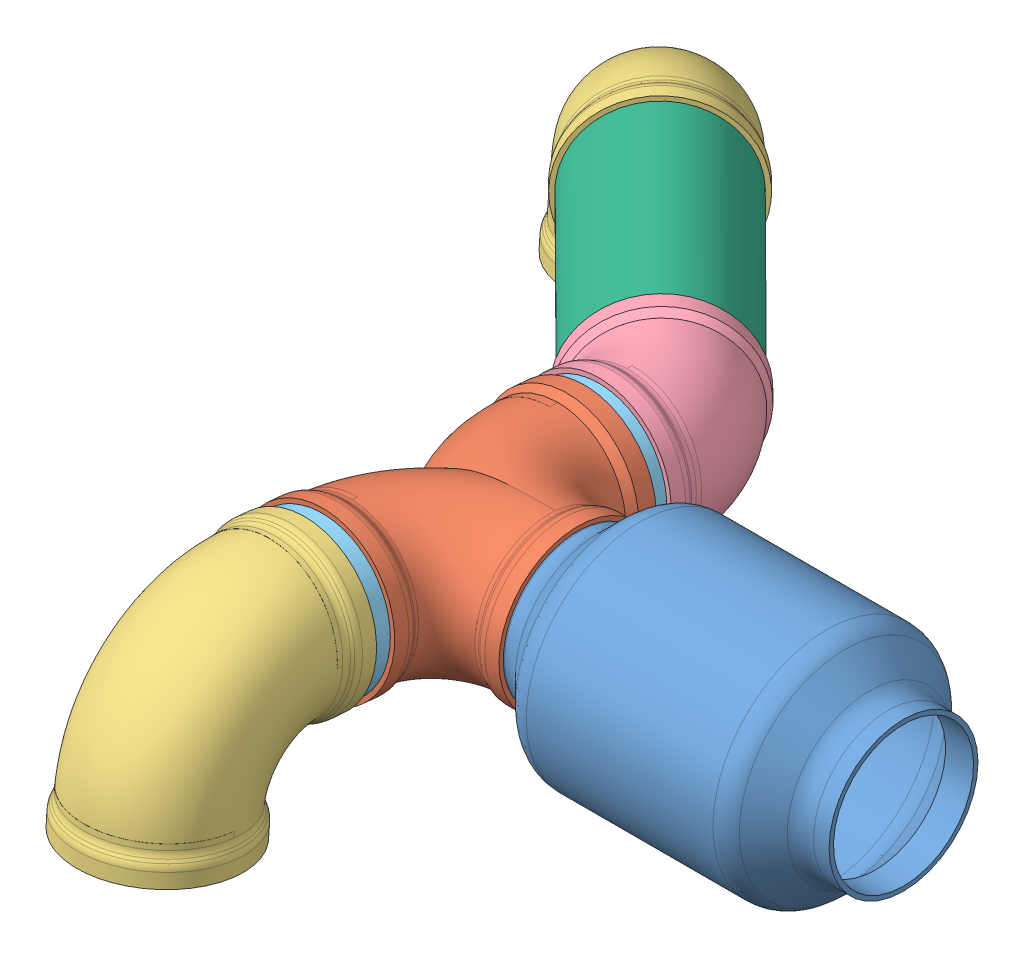
SolidWorks assembly VENTILATION ASSEMBLY, configuration Default. Lengths in mm.
Overall size (657.37 227.14 752.82).
8 component instances, 6 part files, 14 mates.
Components (placement in the parent):
- VENT PUMP-1: VENT PUMP [Default] at (137.9491 134.7321 160.6703) size (246.38 165.1 165.1)
- T CONNECTION-1: T CONNECTION [Default] at (6.0106 134.7321 160.6703) x (0 -0.092149 -0.995745) z (1 0 0) size (190.5 121.73 152.4)
- 90 DEG CONNECTION-1: 90 DEG CONNECTION [Default] at (-70.1894 146.4791 287.6068) x (-0.02224 0.995499 -0.092126) z (0 -0.092149 -0.995745) size (152.4 114.3 152.4)
- 45 DEG CONNECTION-1: 45 DEG CONNECTION [Default] at (-70.1894 123.206 36.1221) x (0.999753 0.022145 -0.002049) z (0 0.092149 0.995745) size (133.42 114.53 126.88)
- 1.33 INCH-1: 1.33 INCH [Default] at (-70.1894 142.56 245.2573) x (0 0.092149 0.995745) z (-0.923944 -0.3809 0.03525) size (33.78 107.95 107.95)
- 1.33 INCH-2: 1.33 INCH [Default] at (-70.1894 124.0122 44.8333) x (0 0.092149 0.995745) z (-0.987138 -0.159192 0.014732) size (33.78 107.95 107.95)
- 8 INCH-3: 8 INCH [Default] at (-254.1069 99.2716 -178.1101) x (0.706932 0.080818 0.702649) z (0.56882 -0.655385 -0.496905) size (228.6 107.95 107.95)
- 90 DEG CONNECTION-2: 90 DEG CONNECTION [Default] at (-260.2915 98.5646 -184.2572) x (-0.02224 0.995499 -0.092126) z (0.706932 0.080818 0.702649) size (152.4 114.3 152.4)
Mates (geometry in assembly coordinates):
- Concentric1: concentric anti-aligned: cylinder of VENT PUMP-1 through (14.7591 134.7321 160.6703) axis (-1 0 0) radius 53.975; cylinder of T CONNECTION-1 through (25.0606 134.7321 160.6703) axis (1 0 0) radius 53.975
- Coincident1: coincident anti-aligned: circle of VENT PUMP-1; circle of T CONNECTION-1
- Coincident2: coincident anti-aligned: circle of T CONNECTION-1; circle of ?
- Coincident3: coincident aligned: circle of ?; circle of 90 DEG CONNECTION-1
- Coincident4: coincident aligned: circle of T CONNECTION-1; circle of ?
- Coincident5: coincident aligned: circle of ?; circle of 45 DEG CONNECTION-1
- Coincident6: coincident aligned: circle of T CONNECTION-1; circle of 1.33 INCH-1
- Coincident7: coincident anti-aligned: circle of 90 DEG CONNECTION-1; circle of 1.33 INCH-1
- Coincident8: coincident aligned: circle of T CONNECTION-1; circle of 1.33 INCH-2
- Coincident9: coincident aligned: circle of 45 DEG CONNECTION-1; circle of 1.33 INCH-2
- Coincident10: coincident aligned: circle of 45 DEG CONNECTION-1; plane of 8 INCH-3 through (-92.5023 117.7466 -17.4845) normal (0.706932 0.080818 0.702649)
- Concentric8: concentric aligned: circle of 45 DEG CONNECTION-1; circle of 8 INCH-3
- Coincident11: coincident aligned: circle of 8 INCH-3; circle of 90 DEG CONNECTION-2
- Parallel2: parallel aligned: plane of 90 DEG CONNECTION-1 through (-10.9352 59.9452 372.1405) normal (0.02224 -0.995499 0.092126); plane of 90 DEG CONNECTION-2 through (-352.4425 0.4139 -188.702) normal (0.02224 -0.995499 0.092126)
